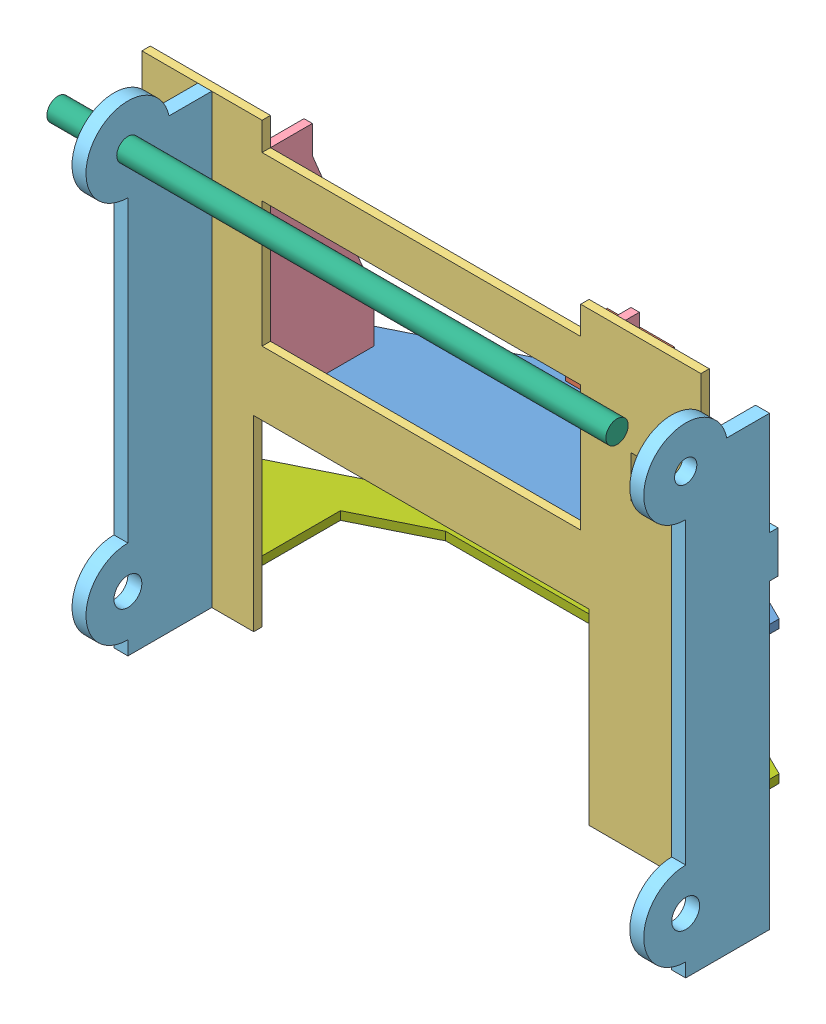
SolidWorks assembly 夹爪支架, configuration 默认. Lengths in mm.
Overall size (224.57 172 124.5).
11 component instances, 8 part files, 20 mates.
Components (placement in the parent):
- 轨与夹子链接件1-1: 轨与夹子链接件1 [默认] at (101.2797 50.8674 247.7393) x (1 0 0) z (0 1 0) size (200 76.5 3)
- 双螺丝角码-1: 双螺丝角码 [默认] at (101.2797 53.8674 199.7393) x (1 0 0) z (0 1 0) size (24 15 15)
- 支架大板-1: 支架大板 [默认] at (101.2797 50.8674 267.7393) x (-1 0 0) z (0 0 1) size (200 160 3)
- 轨与夹子链接件3-1: 轨与夹子链接件3 [默认] at (41.2797 53.8674 267.7393) x (0 0 -1) z (-1 0 0) size (37 83 3)
- 双螺丝角码-2: 双螺丝角码 [默认] at (101.2797 2.8674 199.7393) x (-1 0 0) z (0 -1 0) size (24 15 15)
- 轴轮固定板-1: 轴轮固定板 [默认] at (26.2797 63.8674 285.7393) x (0 1 0) z (-1 0 0) size (172 48 5)
- 零件10^夹爪支架-1: 零件10^夹爪支架 [默认] at origin (virtual)
- 轴-1: 轴 [默认] at (101.2797 140.8674 300.7393) x (0 -0.332029 -0.943269) z (-1 0 0) size (8 8 200)
- 轨与夹子链接件3-2: 轨与夹子链接件3 [默认] at (158.2797 53.8674 267.7393) x (0 0 -1) z (-1 0 0) size (37 83 3)
- 轴轮固定板-3: 轴轮固定板 [默认] at (225.849 63.8674 285.7393) x (0 1 0) z (-1 0 0) size (172 48 5)
- 轨与夹子链接件2-2: 轨与夹子链接件2 [默认] at (101.2797 3036.8486 192.2393) x (1 0 0) z (0 1 0) size (200 76.5 3)
Mates (geometry in assembly coordinates):
- 同心3: concentric aligned: cylinder of 轨与夹子链接件1-1 through (92.2797 48.8674 202.2393) axis (0 1 0) radius 1.5; cylinder of 双螺丝角码-1 through (92.2797 53.8674 202.2393) axis (0 1 0) radius 1.25
- 同心4: concentric aligned: cylinder of 轨与夹子链接件1-1 through (110.2797 48.8674 202.2393) axis (0 1 0) radius 1.5; cylinder of 双螺丝角码-1 through (110.2797 53.8674 202.2393) axis (0 1 0) radius 1.25
- 重合3: coincident anti-aligned: plane of 轨与夹子链接件1-1 through (101.2797 53.8674 247.7393) normal (0 1 0); plane of 双螺丝角码-1 through (101.2797 53.8674 199.7393) normal (0 -1 0)
- 重合7: coincident aligned: plane of 支架大板-1 through (44.2797 143.8674 270.7393) normal (1 0 0); plane of 轨与夹子链接件3-1 through (44.2797 53.8674 267.7393) normal (1 0 0)
- 重合8: coincident anti-aligned: plane of 轨与夹子链接件1-1 through (101.2797 53.8674 247.7393) normal (0 1 0); plane of 轨与夹子链接件3-1 through (44.2797 53.8674 245.7393) normal (0 -1 0)
- 重合10: coincident anti-aligned: plane of 支架大板-1 through (101.2797 50.8674 267.7393) normal (0 0 -1); plane of 轨与夹子链接件3-1 through (44.2797 53.8674 267.7393) normal (0 0 1)
- 重合11: coincident anti-aligned: plane of 轨与夹子链接件1-1 through (1.2797 53.8674 267.7393) normal (0 0 1); plane of 支架大板-1 through (101.2797 50.8674 267.7393) normal (0 0 -1)
- 重合12: coincident aligned: plane of 轨与夹子链接件1-1 through (201.2797 53.8674 242.7393) normal (1 0 0); plane of 支架大板-1 through (201.2797 -16.1326 270.7393) normal (1 0 0)
- 同心5: concentric anti-aligned: cylinder of 轴轮固定板-1 through (26.2797 140.8674 300.7393) axis (-1 0 0) radius 4; cylinder of 轴-1 through (1.2797 140.8674 300.7393) axis (1 0 0) radius 4
- 重合14: coincident anti-aligned: plane of 支架大板-1 through (101.2797 50.8674 270.7393) normal (0 0 1); plane of 轴轮固定板-1 through (21.2797 -16.1326 270.7393) normal (0 0 -1)
- 距离1: distance = 20 mm aligned: plane of 轴轮固定板-1 through (21.2797 63.8674 285.7393) normal (-1 0 0); plane of 支架大板-1 through (1.2797 -16.1326 270.7393) normal (-1 0 0)
- 重合16: coincident aligned: plane of 支架大板-1 through (1.2797 143.8674 270.7393) normal (0 1 0); plane of 轴轮固定板-1 through (21.2797 143.8674 300.7393) normal (0 1 0)
- 重合17: coincident aligned: plane of 轨与夹子链接件1-1 through (101.2797 50.8674 247.7393) normal (0 -1 0); plane of 支架大板-1 through (41.2797 50.8674 270.7393) normal (0 -1 0)
- 重合18: coincident anti-aligned: plane of 轨与夹子链接件1-1 through (101.2797 50.8674 247.7393) normal (1 0 0); plane of 轴-1 through (101.2797 140.8674 300.7393) normal (-1 0 0)
- 重合23: coincident anti-aligned: plane of 支架大板-1 through (101.2797 50.8674 267.7393) normal (0 0 -1); plane of 轨与夹子链接件2-2 through (201.2797 5.8674 267.7393) normal (0 0 1)
- 距离7: distance = 45 mm anti-aligned: plane of 轨与夹子链接件1-1 through (101.2797 50.8674 247.7393) normal (0 -1 0); plane of 轨与夹子链接件2-2 through (101.2797 5.8674 192.2393) normal (0 1 0)
- 同心6: concentric anti-aligned: cylinder of 双螺丝角码-2 through (110.2797 2.8674 202.2393) axis (0 -1 0) radius 1.25; cylinder of 轨与夹子链接件2-2 through (110.2797 2.8674 202.2393) axis (0 1 0) radius 1.5
- 同心7: concentric anti-aligned: cylinder of 双螺丝角码-2 through (92.2797 2.8674 202.2393) axis (0 -1 0) radius 1.25; cylinder of 轨与夹子链接件2-2 through (92.2797 2.8674 202.2393) axis (0 1 0) radius 1.5
- 重合25: coincident anti-aligned: plane of 双螺丝角码-2 through (101.2797 2.8674 199.7393) normal (0 1 0); plane of 轨与夹子链接件2-2 through (101.2797 2.8674 192.2393) normal (0 -1 0)
- 重合26: coincident aligned: plane of 支架大板-1 through (201.2797 -16.1326 270.7393) normal (1 0 0); plane of 轨与夹子链接件2-2 through (201.2797 5.8674 242.7393) normal (1 0 0)
